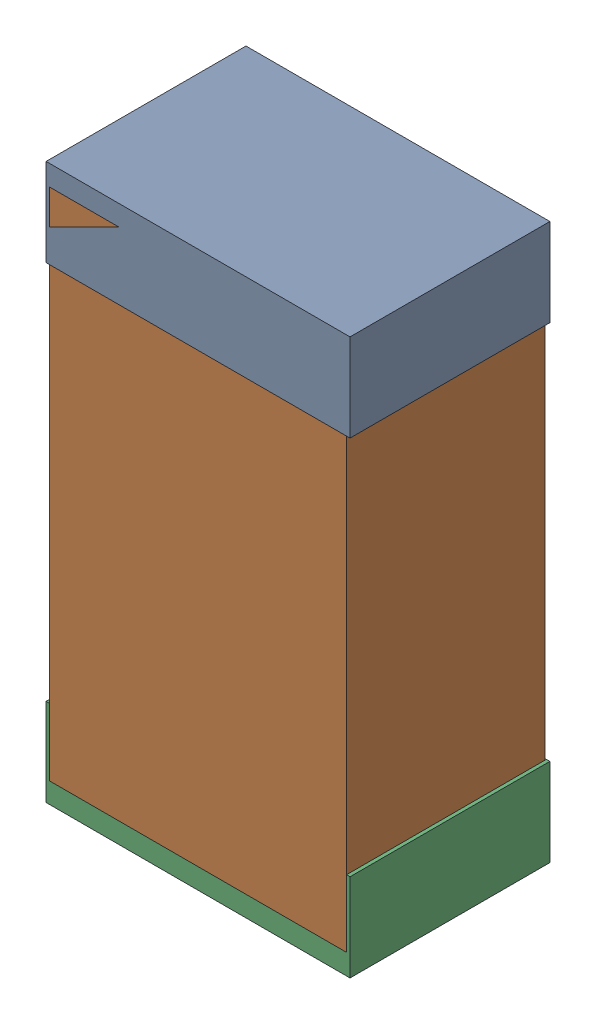
SolidWorks assembly R48Kanaloa_v2.0.0_Motor, configuration Default. Lengths in mm.
Overall size (1.3 2.38 0.85).
6 component instances, 2 part files, 0 mates.
Components (placement in the parent):
- 330415056-1: 330415056 [Default] at (51.054 155.686 -1.9574) size (1.3 0.38 0.85)
  - Extruded_2-1: Extruded_2 [Default] at origin size (1.3 0.38 0.85)
- 334787376-1: 334787376 [Default] at (51.054 154.686 -1.9524) size (1.27 2.2 0.85)
  - Extruded_16-1: Extruded_16 [Default] at origin size (1.27 2.2 0.85)
- 330415056-2: 330415056 [Default] at (51.054 153.686 -1.9574) size (1.3 0.38 0.85)
  - Extruded_2-1: Extruded_2 [Default] at origin size (1.3 0.38 0.85)
